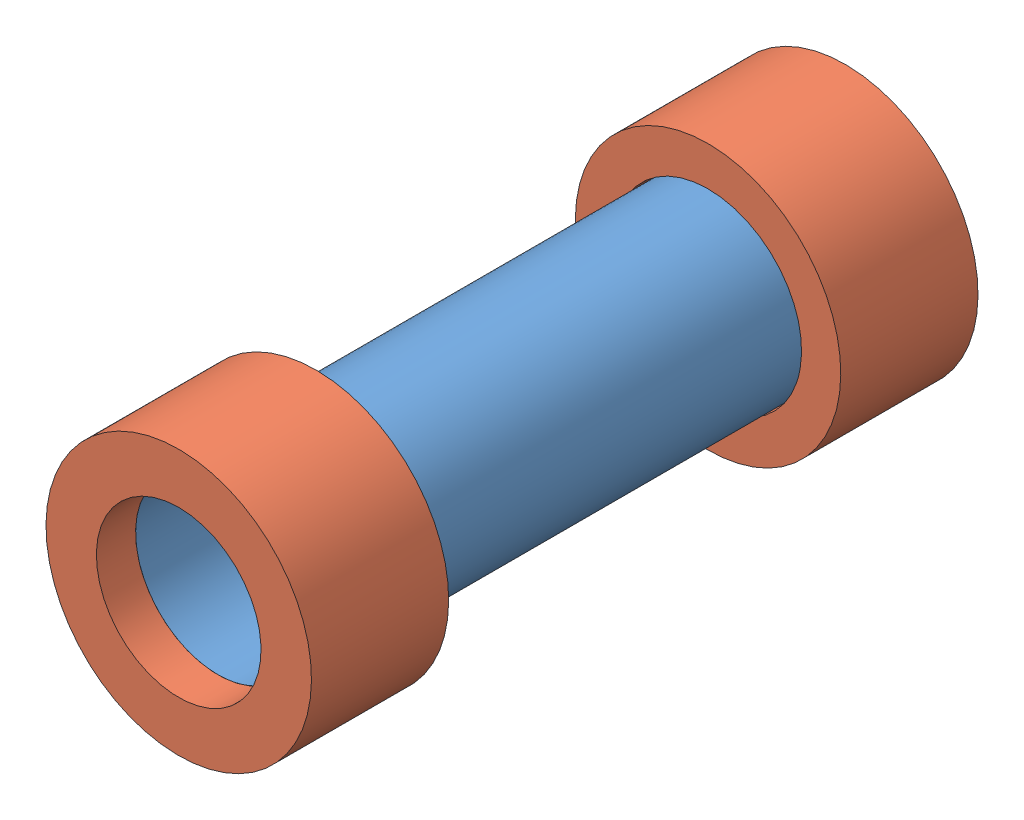
SolidWorks assembly StorageCapsule, configuration Default. Lengths in mm.
Overall size (22.05 22.05 43.18).
3 component instances, 2 part files, 4 mates.
Components (placement in the parent):
- Capsule Body-1: Capsule Body [Default] at (-35.2494 1.4555 -1.4383) size (11.94 11.94 38.1)
- Caps-1: Caps [Default] at (-35.2494 1.4555 36.6617) x (-0.939504 -0.342537 0) z (0 0 -1) size (17.2 17.2 8.89)
- Caps-2: Caps [Default] at (-35.2494 1.4555 -1.4383) x (0.968006 -0.250926 0) z (0 0 1) size (17.2 17.2 8.89)
Mates (geometry in assembly coordinates):
- Concentric1: concentric aligned: cylinder of Capsule Body-1 through (-35.2494 1.4555 -1.4383) axis (0 0 1) radius 4.445; cylinder of Caps-1 through (-35.2494 1.4555 30.3117) axis (0 0 1) radius 6.0585
- Concentric2: concentric anti-aligned: circle of Capsule Body-1; cylinder of Caps-2 through (-35.2494 1.4555 4.9117) axis (0 0 -1) radius 6.0585
- Coincident1: coincident anti-aligned: plane of Capsule Body-1 through (-35.2494 1.4555 36.6617) normal (0 0 1); plane of Caps-1 through (-35.2494 1.4555 36.6617) normal (0 0 -1)
- Coincident2: coincident anti-aligned: plane of Capsule Body-1 through (-35.2494 1.4555 -1.4383) normal (0 0 -1); plane of Caps-2 through (-35.2494 1.4555 -1.4383) normal (0 0 1)
